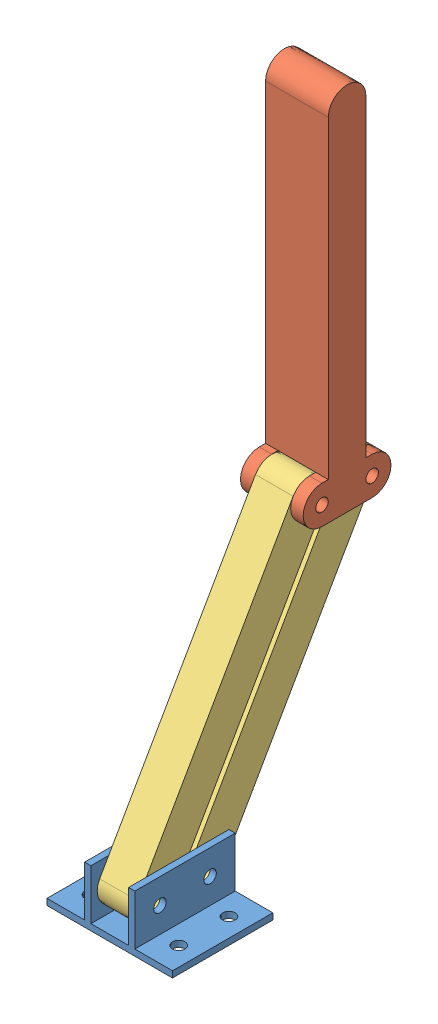
SolidWorks assembly Arm Assem, configuration Default. Lengths in mm.
Overall size (63.5 331.46 130.25).
4 component instances, 3 part files, 7 mates.
Components (placement in the parent):
- Mounting Bracket-1: Mounting Bracket [Default] at origin size (63.5 28.57 50.8)
- Contact Arm-1: Contact Arm [Default] at (15.875 153.6554 -66.1551) x (0 1 0) z (1 0 0) size (187.33 44.45 31.75)
- Parallel Arm-2: Parallel Arm [Default] at (41.275 84.7652 -1.3275) x (0 0.867908 -0.496725) z (0 0.496725 0.867908) size (177.8 19.05 19.05)
- Parallel Arm-3: Parallel Arm [Default] at (41.275 84.7652 -26.7275) x (0 0.867908 -0.496725) z (0 0.496725 0.867908) size (177.8 19.05 19.05)
Mates (geometry in assembly coordinates):
- Concentric1: concentric: cylinder of Mounting Bracket-1 through (63.5 15.875 12.7) axis (-1 0 0) radius 3.175; cylinder of Parallel Arm-3 through (22.225 15.875 12.7) axis (1 0 0) radius 3.175
- Coincident1: coincident: plane of Mounting Bracket-1 through (41.275 28.575 50.8) normal (-1 0 0); plane of Parallel Arm-3 through (41.275 15.875 12.7) normal (1 0 0)
- Concentric2: concentric: cylinder of Mounting Bracket-1 through (63.5 15.875 38.1) axis (-1 0 0) radius 3.175; cylinder of Parallel Arm-2 through (22.225 15.875 38.1) axis (1 0 0) radius 3.175
- Coincident2: coincident: plane of Mounting Bracket-1 through (22.225 3.175 50.8) normal (1 0 0); plane of Parallel Arm-2 through (22.225 15.875 38.1) normal (-1 0 0)
- Concentric4: concentric: cylinder of Contact Arm-1 through (47.625 153.6554 -66.1551) axis (-1 0 0) radius 3.175; cylinder of Parallel Arm-3 through (22.225 153.6554 -66.1551) axis (1 0 0) radius 3.175
- Coincident3: coincident: plane of Contact Arm-1 through (22.225 163.1804 -66.1551) normal (1 0 0); plane of Parallel Arm-3 through (22.225 15.875 12.7) normal (-1 0 0)
- Concentric5: concentric: cylinder of Contact Arm-1 through (47.625 153.6554 -40.7551) axis (-1 0 0) radius 3.175; cylinder of Parallel Arm-2 through (22.225 153.6554 -40.7551) axis (1 0 0) radius 3.175
